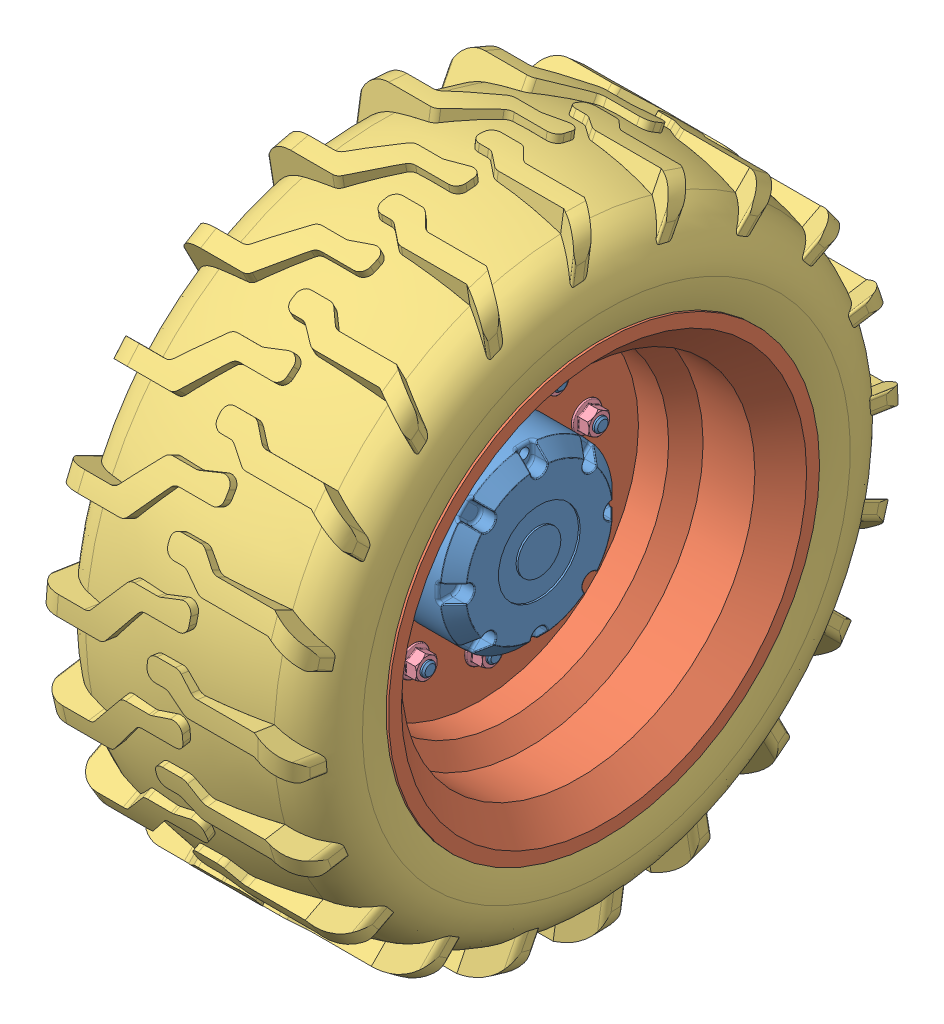
SolidWorks assembly tyre assembly, configuration Default. Lengths in mm.
Overall size (367.75 835.89 835.89).
13 component instances, 4 part files, 26 mates.
Components (placement in the parent):
- axle-2: axle [Default] at (36.1168 112.2987 281.9077) size (290 300 300)
- rim-2: rim [Default] at (141.1168 112.2987 281.9077) size (300 500 500)
- tyre-2: tyre [Default] at (141.1168 112.2987 281.9077) x (1 0 0) z (0 0.152309 0.988333) size (305.49 732.83 732.83)
- hex flange nut_am-3: hex flange nut_am [B18.2.2.4M - Hex flange nut, M16 x 2 --N] at (162.1168 217.4709 205.4956) x (0 0 -1) z (1 0 0) size (34.5 34.5 16)
- hex flange nut_am-4: hex flange nut_am [B18.2.2.4M - Hex flange nut, M16 x 2 --N] at (162.1168 152.4709 158.2703) x (0 0 -1) z (1 0 0) size (34.5 34.5 16)
- hex flange nut_am-5: hex flange nut_am [B18.2.2.4M - Hex flange nut, M16 x 2 --N] at (162.1168 72.1265 158.2703) x (0 -0.874263 0.485453) z (1 0 0) size (34.5 34.5 16)
- hex flange nut_am-7: hex flange nut_am [B18.2.2.4M - Hex flange nut, M16 x 2 --N] at (162.1168 7.1265 205.4956) x (0 0 -1) z (1 0 0) size (34.5 34.5 16)
- hex flange nut_am-8: hex flange nut_am [B18.2.2.4M - Hex flange nut, M16 x 2 --N] at (162.1168 -17.7013 281.9077) x (0 0 -1) z (1 0 0) size (34.5 34.5 16)
- hex flange nut_am-9: hex flange nut_am [B18.2.2.4M - Hex flange nut, M16 x 2 --N] at (162.1168 7.1265 358.3197) x (0 0 -1) z (1 0 0) size (34.5 34.5 16)
- hex flange nut_am-10: hex flange nut_am [B18.2.2.4M - Hex flange nut, M16 x 2 --N] at (162.1168 72.1265 405.545) x (0 0 -1) z (1 0 0) size (34.5 34.5 16)
- hex flange nut_am-11: hex flange nut_am [B18.2.2.4M - Hex flange nut, M16 x 2 --N] at (162.1168 152.4709 405.545) x (0 0 -1) z (1 0 0) size (34.5 34.5 16)
- hex flange nut_am-12: hex flange nut_am [B18.2.2.4M - Hex flange nut, M16 x 2 --N] at (162.1168 217.4709 358.3197) x (0 0 -1) z (1 0 0) size (34.5 34.5 16)
- hex flange nut_am-13: hex flange nut_am [B18.2.2.4M - Hex flange nut, M16 x 2 --N] at (162.1168 242.2987 281.9077) x (0 0 -1) z (1 0 0) size (34.5 34.5 16)
Mates (geometry in assembly coordinates):
- Concentric1: concentric: cylinder of assembly; cylinder of assembly; cylinder of rim-2 through (141.1168 112.2987 281.9077) axis (1 0 0) radius 250; cylinder of tyre-2 through (141.1168 112.2987 281.9077) axis (1 0 0) radius 240
- Coincident1: coincident: plane of assembly; plane of assembly; plane of rim-2 through (141.1168 112.2987 281.9077) normal (1 0 0); plane of tyre-2 through (141.1168 112.2987 281.9077) normal (1 0 0)
- Concentric2: concentric: cylinder of assembly; cylinder of assembly; cylinder of axle-2 through (36.1168 112.2987 281.9077) axis (-1 0 0) radius 150; cylinder of rim-2 through (141.1168 112.2987 281.9077) axis (1 0 0) radius 100
- Coincident2: coincident: plane of assembly; plane of assembly; plane of axle-2 through (136.1168 212.2987 281.9077) normal (1 0 0); plane of rim-2 through (136.1168 297.2987 281.9077) normal (-1 0 0)
- Concentric4: concentric: cylinder of assembly; cylinder of assembly; cylinder of axle-2 through (166.1168 242.2987 281.9077) axis (-1 0 0) radius 8; cylinder of rim-2 through (136.1168 242.2987 281.9077) axis (1 0 0) radius 8
- Concentric6: concentric: cylinder of assembly; cylinder of assembly; cylinder of rim-2 through (136.1168 217.4709 205.4956) axis (1 0 0) radius 8; cylinder of hex flange nut_am-3 through (137.0793 217.4709 205.4956) axis (1 0 0) radius 8
- Coincident4: coincident: plane of assembly; plane of assembly; plane of rim-2 through (146.1168 297.2987 281.9077) normal (1 0 0); plane of hex flange nut_am-3 through (146.1168 231.3273 205.4956) normal (-1 0 0)
- Concentric7: concentric: cylinder of assembly; cylinder of assembly; cylinder of rim-2 through (136.1168 152.4709 158.2703) axis (1 0 0) radius 8; cylinder of hex flange nut_am-4 through (137.0793 152.4709 158.2703) axis (1 0 0) radius 8
- Coincident5: coincident: plane of assembly; plane of assembly; plane of rim-2 through (146.1168 297.2987 281.9077) normal (1 0 0); plane of hex flange nut_am-4 through (146.1168 166.3273 158.2703) normal (-1 0 0)
- Concentric8: concentric: cylinder of assembly; cylinder of assembly; cylinder of rim-2 through (136.1168 72.1265 158.2703) axis (1 0 0) radius 8; cylinder of hex flange nut_am-5 through (137.0793 72.1265 158.2703) axis (1 0 0) radius 8
- Coincident6: coincident: plane of assembly; plane of assembly; plane of rim-2 through (146.1168 297.2987 281.9077) normal (1 0 0); plane of hex flange nut_am-5 through (146.1168 65.3999 146.1562) normal (-1 0 0)
- Concentric9: concentric: cylinder of axle-2 through (166.1168 7.1265 205.4956) axis (-1 0 0) radius 8; cylinder of ? through (172.3474 7.1265 205.4956) axis (-1 0 0) radius 8
- Concentric10: concentric: cylinder of assembly; cylinder of assembly; cylinder of rim-2 through (136.1168 7.1265 205.4956) axis (1 0 0) radius 8; cylinder of hex flange nut_am-7 through (137.0793 7.1265 205.4956) axis (1 0 0) radius 8
- Coincident7: coincident: plane of assembly; plane of assembly; plane of rim-2 through (146.1168 297.2987 281.9077) normal (1 0 0); plane of hex flange nut_am-7 through (146.1168 20.9829 205.4956) normal (-1 0 0)
- Concentric11: concentric: cylinder of assembly; cylinder of assembly; cylinder of rim-2 through (136.1168 -17.7013 281.9077) axis (1 0 0) radius 8; cylinder of hex flange nut_am-8 through (137.0793 -17.7013 281.9077) axis (1 0 0) radius 8
- Coincident8: coincident: plane of assembly; plane of assembly; plane of rim-2 through (146.1168 297.2987 281.9077) normal (1 0 0); plane of hex flange nut_am-8 through (146.1168 -3.8449 281.9077) normal (-1 0 0)
- Concentric12: concentric: cylinder of assembly; cylinder of assembly; cylinder of rim-2 through (136.1168 7.1265 358.3197) axis (1 0 0) radius 8; cylinder of hex flange nut_am-9 through (137.0793 7.1265 358.3197) axis (1 0 0) radius 8
- Coincident9: coincident: plane of assembly; plane of assembly; plane of rim-2 through (146.1168 297.2987 281.9077) normal (1 0 0); plane of hex flange nut_am-9 through (146.1168 20.9829 358.3197) normal (-1 0 0)
- Concentric13: concentric: cylinder of assembly; cylinder of assembly; cylinder of rim-2 through (136.1168 72.1265 405.545) axis (1 0 0) radius 8; cylinder of hex flange nut_am-10 through (137.0793 72.1265 405.545) axis (1 0 0) radius 8
- Coincident10: coincident: plane of assembly; plane of assembly; plane of rim-2 through (146.1168 297.2987 281.9077) normal (1 0 0); plane of hex flange nut_am-10 through (146.1168 85.9829 405.545) normal (-1 0 0)
- Concentric14: concentric: cylinder of assembly; cylinder of assembly; cylinder of rim-2 through (136.1168 152.4709 405.545) axis (1 0 0) radius 8; cylinder of hex flange nut_am-11 through (137.0793 152.4709 405.545) axis (1 0 0) radius 8
- Coincident11: coincident: plane of assembly; plane of assembly; plane of rim-2 through (146.1168 297.2987 281.9077) normal (1 0 0); plane of hex flange nut_am-11 through (146.1168 166.3273 405.545) normal (-1 0 0)
- Concentric15: concentric: cylinder of assembly; cylinder of assembly; cylinder of rim-2 through (136.1168 217.4709 358.3197) axis (1 0 0) radius 8; cylinder of hex flange nut_am-12 through (137.0793 217.4709 358.3197) axis (1 0 0) radius 8
- Coincident12: coincident: plane of assembly; plane of assembly; plane of rim-2 through (146.1168 297.2987 281.9077) normal (1 0 0); plane of hex flange nut_am-12 through (146.1168 231.3273 358.3197) normal (-1 0 0)
- Concentric16: concentric: cylinder of assembly; cylinder of assembly; cylinder of rim-2 through (136.1168 242.2987 281.9077) axis (1 0 0) radius 8; cylinder of hex flange nut_am-13 through (137.0793 242.2987 281.9077) axis (1 0 0) radius 8
- Coincident13: coincident: plane of assembly; plane of assembly; plane of rim-2 through (146.1168 297.2987 281.9077) normal (1 0 0); plane of hex flange nut_am-13 through (146.1168 256.1551 281.9077) normal (-1 0 0)
